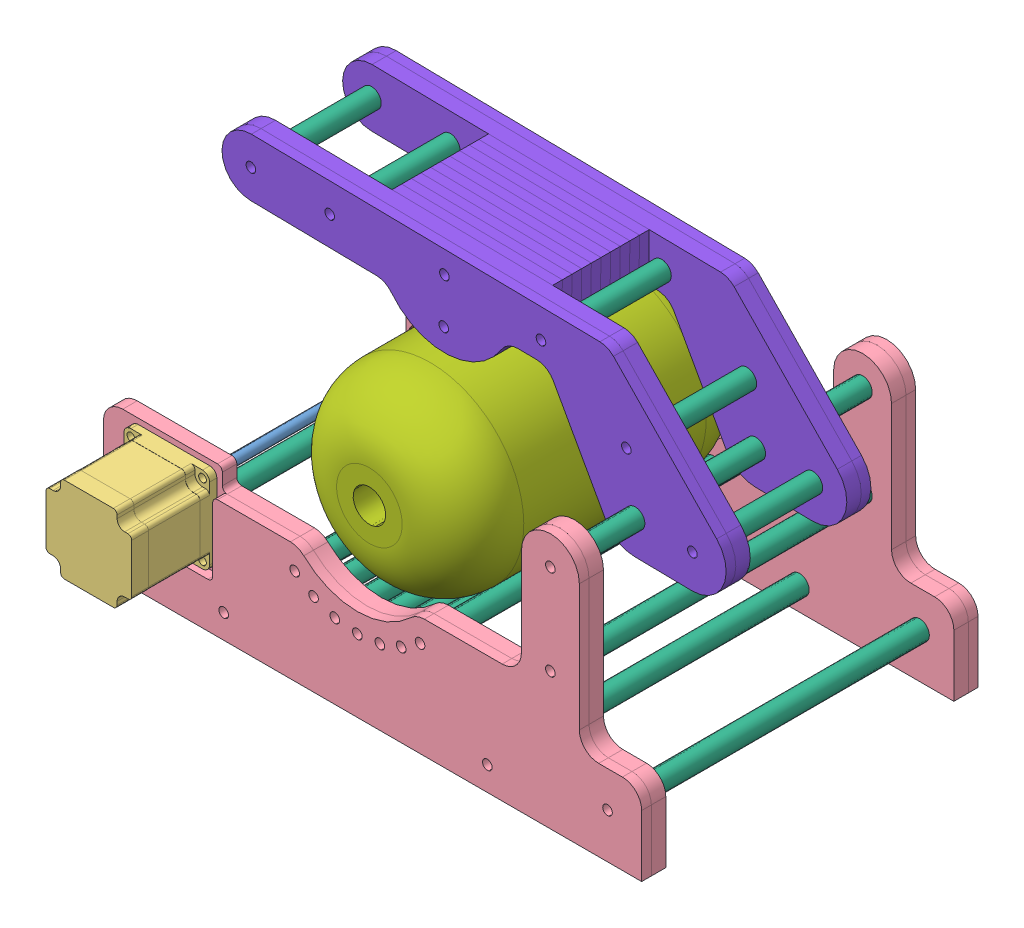
SolidWorks assembly ULTIMA_Respirator_main_assembly, configuration Défaut. Lengths in mm.
Overall size (361.61 241.93 320.57).
31 component instances, 8 part files, 27 mates.
Components (placement in the parent):
- McMaster-1257K65-1: McMaster-1257K65 [1257K114] at origin size (6.35 6.35 152.4)
- McMaster-6208K524-1: McMaster-6208K524 [6208K524] at (0 0 -87.63) x (0.967765 0.251857 0) z (0 0 1) size (25.41 25.4 38.1)
- Nema 23 Stepper Motor-1: Nema 23 Stepper Motor [Défaut] at (0 0 -111.455) size (56.4 56.4 76.6)
- ULTIMA_Respirator-01-1: ULTIMA_Respirator-01 [cote_droit] at (0 0 -111.455) size (360.46 168.25 15.88)
- McMaster-61005K311-1: McMaster-61005K311 [61005K311] at (0 0 76.3588) x (0 0 -1) z (0.997278 0.073738 0) size (25.4 15.88 15.87)
- Nema 23 Stepper Motor-2: Nema 23 Stepper Motor [Défaut] at (0 0 97.1175) x (-1 0 0) z (0 0 -1) size (56.4 56.4 76.6)
- ULTIMA_Respirator-01-2: ULTIMA_Respirator-01 [cote_gauche] at (0 0 87.5925) size (360.46 168.25 15.88)
- McMaster-89965K492-1: McMaster-89965K492 [8in] at (-31.6257 -46.1559 97.1175) x (0 0 -1) z (0.005772 0.999983 0) size (208.57 12.7 12.7)
- McMaster-89965K492-3: McMaster-89965K492 [8in] at (85.76 2.5142 97.1175) x (0 0 -1) z (0.005772 0.999983 0) size (208.57 12.7 12.7)
- McMaster-89965K492-4: McMaster-89965K492 [8in] at (98.1716 -5.7789 97.1175) x (0 0 -1) z (0.005772 0.999983 0) size (208.57 12.7 12.7)
- McMaster-89965K492-5: McMaster-89965K492 [8in] at (127 -12.7 97.1175) x (0 0 -1) z (0.005772 0.999983 0) size (208.57 12.7 12.7)
- McMaster-89965K492-6: McMaster-89965K492 [8in] at (141.8238 -10.9455 97.1175) x (0 0 -1) z (0.005772 0.999983 0) size (208.57 12.7 12.7)
- McMaster-89965K492-7: McMaster-89965K492 [8in] at (112.1762 -10.9455 97.1175) x (0 0 -1) z (0.005772 0.999983 0) size (208.57 12.7 12.7)
- McMaster-89965K492-8: McMaster-89965K492 [8in] at (155.8284 -5.7789 97.1175) x (0 0 -1) z (0.005772 0.999983 0) size (208.57 12.7 12.7)
- McMaster-89965K492-9: McMaster-89965K492 [8in] at (168.24 2.5142 97.1175) x (0 0 -1) z (0.005772 0.999983 0) size (208.57 12.7 12.7)
- McMaster-89965K492-10: McMaster-89965K492 [8in] at (39.0404 -44.4791 97.1175) x (0 0 -1) z (0.005772 0.999983 0) size (208.57 12.7 12.7)
- McMaster-89965K492-11: McMaster-89965K492 [8in] at (212.5171 -44.4791 97.1175) x (0 0 -1) z (0.005772 0.999983 0) size (208.57 12.7 12.7)
- McMaster-89965K492-12: McMaster-89965K492 [8in] at (291.5916 -30.7687 97.1175) x (0 0 -1) z (0.005772 0.999983 0) size (208.57 12.7 12.7)
- McMaster-89965K492-13: McMaster-89965K492 [8in] at (254 29.6105 97.1175) x (0 0 -1) z (0.005772 0.999983 0) size (208.57 12.7 12.7)
- McMaster-89965K492-14: McMaster-89965K492 [8in] at (254 88.9 97.1175) x (0 0 -1) z (0.005772 0.999983 0) size (208.57 12.7 12.7)
- approximative_ambubag_pump_volume-1: approximative_ambubag_pump_volume [Défaut] at (127.2504 56.684 -4.1981) x (0 0 1) z (-0.993068 -0.117537 0) size (200 123.16 123.16)
- ULTIMA_Respirator-02-1: ULTIMA_Respirator-02 [cote_gauche] at (-1.3727 4.0237 31.75) x (0.999875 -0.015798 0) z (0 0 1) size (332.87 211.28 47.62)
- McMaster-89965K492-16: McMaster-89965K492 [3.25] at (1.1278 162.2879 41.275) x (0 0 -1) z (0.005772 0.999983 0) size (82.55 12.7 12.7)
- McMaster-89965K492-17: McMaster-89965K492 [3.25] at (52.9818 161.4687 41.275) x (0 0 -1) z (0.005772 0.999983 0) size (82.55 12.7 12.7)
- McMaster-89965K492-18: McMaster-89965K492 [3.25] at (128.4323 164.7062 41.275) x (0 0 -1) z (0.005772 0.999983 0) size (82.55 12.7 12.7)
- McMaster-89965K492-19: McMaster-89965K492 [3.25] at (127.961 134.8809 41.275) x (0 0 -1) z (0.005772 0.999983 0) size (82.55 12.7 12.7)
- McMaster-89965K492-20: McMaster-89965K492 [3.25] at (191.9677 159.2727 41.275) x (0 0 -1) z (0.005772 0.999983 0) size (82.55 12.7 12.7)
- McMaster-89965K492-21: McMaster-89965K492 [3.25] at (248.1556 125.8527 41.275) x (0 0 -1) z (0.005772 0.999983 0) size (82.55 12.7 12.7)
- McMaster-89965K492-22: McMaster-89965K492 [3.25] at (291.587 88.3061 41.275) x (0 0 -1) z (0.005772 0.999983 0) size (82.55 12.7 12.7)
- McMaster-89965K492-23: McMaster-89965K492 [3.25] at (1.1278 162.2879 41.275) x (0 0 -1) z (0.005772 0.999983 0) size (82.55 12.7 12.7)
- ULTIMA_Respirator-02-3: ULTIMA_Respirator-02 [cote_droite] at (-1.3727 4.0237 -41.275) x (0.999875 -0.015798 0) z (0 0 1) size (332.87 211.28 47.62)
Mates (geometry in assembly coordinates):
- Concentric1: concentric: cylinder of Nema 23 Stepper Motor-1 through (-0.1601 -1.1209 114.9) axis (0 0 -1) radius 3.175; cylinder of ? through (-0.1601 -1.1209 111.4419) axis (0 0 1) radius 3.175
- Concentric2: concentric: cylinder of Nema 23 Stepper Motor-1 through (0 0 -90.855) axis (0 0 -1) radius 3.175; cylinder of McMaster-6208K524-1 through (0 0 -106.68) axis (0 0 1) radius 3.175
- Concentric3: concentric: cylinder of McMaster-6208K524-1 through (0 0 -68.58) axis (0 0 -1) radius 3.175; cylinder of McMaster-1257K65-1 through (0 0 76.2) axis (0 0 -1) radius 3.175
- Coincident1: coincident: plane of McMaster-6208K524-1 through (0 0 -76.2) normal (0 0 -1); plane of McMaster-1257K65-1 through (0 0 -76.2) normal (0 0 -1)
- Concentric4: concentric: cylinder of McMaster-1257K65-1 through (0 0 76.2) axis (0 0 -1) radius 3.175; cylinder of McMaster-61005K311-1 through (0 0 89.0588) axis (0 0 1) radius 3.175
- Coincident2: coincident: plane of McMaster-1257K65-1 through (0 0 76.2) normal (0 0 1); plane of McMaster-61005K311-1 through (8.5012 -7.3306 76.2) normal (0 0 1)
- Distance1: distance = 3.175 mm: plane of Nema 23 Stepper Motor-1 through (0 0 -109.855) normal (0 0 1); plane of McMaster-6208K524-1 through (0 0 -106.68) normal (0 0 -1)
- Coincident3: coordinate: point of McMaster-1257K65-1; point of assembly
- Parallel1: parallel: plane of McMaster-1257K65-1 through (0 0 0) normal (0 1 0); plane of Nema 23 Stepper Motor-1 through (0 0 -111.455) normal (0 1 0)
- Concentric5: concentric: cylinder of McMaster-61005K311-1 through (0 0 89.0588) axis (0 0 1) radius 3.175; cylinder of Nema 23 Stepper Motor-2 through (0 0 76.5175) axis (0 0 1) radius 3.175
- Coincident4: coincident: plane of McMaster-61005K311-1 through (8.5012 -7.3306 76.5175) normal (0 0 -1); plane of Nema 23 Stepper Motor-2 through (0 0 76.5175) normal (0 0 -1)
- Parallel2: parallel: plane of McMaster-1257K65-1 through (0 0 0) normal (0 1 0); plane of Nema 23 Stepper Motor-2 through (0 0 97.1175) normal (0 1 0)
- Concentric6: concentric: cylinder of Nema 23 Stepper Motor-1 through (0 0 -109.855) axis (0 0 -1) radius 19.05; cylinder of ULTIMA_Respirator-01-1 through (0 0 -101.93) axis (0 0 -1) radius 19.05
- Coincident5: coincident: plane of Nema 23 Stepper Motor-1 through (-23.6 23.6 -111.455) normal (0 0 1); plane of ULTIMA_Respirator-01-1 through (301.356 -19.7831 -111.455) normal (0 0 -1)
- Parallel3: parallel: plane of Nema 23 Stepper Motor-1 through (16.07 28.1 -156.455) normal (0 1 0); plane of ULTIMA_Respirator-01-1 through (-33.7088 31.8249 -101.93) normal (0 1 0)
- Concentric7: concentric: cylinder of Nema 23 Stepper Motor-2 through (0 0 95.5175) axis (0 0 1) radius 19.05; cylinder of ULTIMA_Respirator-01-2 through (0 0 97.1175) axis (0 0 -1) radius 19.05
- Coincident6: coincident: plane of Nema 23 Stepper Motor-2 through (23.6 23.6 97.1175) normal (0 0 -1); plane of ULTIMA_Respirator-01-2 through (301.356 -19.7831 97.1175) normal (0 0 1)
- Parallel4: parallel: plane of Nema 23 Stepper Motor-2 through (-16.07 28.1 142.1175) normal (0 1 0); plane of ULTIMA_Respirator-01-2 through (-33.7088 31.8249 97.1175) normal (0 1 0)
- Concentric9: concentric: cylinder of ULTIMA_Respirator-01-1 through (-31.6257 -46.1559 -101.93) axis (0 0 -1) radius 6.35; cylinder of McMaster-89965K492-1 through (-31.6257 -46.1559 -111.4546) axis (0 0 1) radius 6.35
- Coincident10: coincident: plane of ULTIMA_Respirator-01-2 through (301.356 -19.7831 97.1175) normal (0 0 1); plane of McMaster-89965K492-1 through (-31.6257 -46.1559 97.1175) normal (0 0 1)
- Concentric10: concentric: cylinder of McMaster-89965K492-14 through (254 88.9 -111.4546) axis (0 0 1) radius 6.35; cylinder of ULTIMA_Respirator-02-1 through (254 88.9 41.275) axis (0 0 -1) radius 6.35
- Distance2: distance = 31.75 mm: point of McMaster-1257K65-1; plane of ULTIMA_Respirator-02-1 through (254 88.9 31.75) normal (0 0 -1)
- Concentric11: concentric: cylinder of ULTIMA_Respirator-02-1 through (1.1278 162.2879 41.275) axis (0 0 -1) radius 6.35; cylinder of McMaster-89965K492-16 through (1.1278 162.2879 -41.275) axis (0 0 1) radius 6.35
- Coincident12: coincident: plane of ULTIMA_Respirator-02-1 through (254 88.9 41.275) normal (0 0 1); plane of McMaster-89965K492-16 through (1.1278 162.2879 41.275) normal (0 0 1)
- Concentric12: concentric: cylinder of McMaster-89965K492-14 through (254 88.9 -111.4546) axis (0 0 1) radius 6.35; cylinder of ULTIMA_Respirator-02-3 through (254 88.9 -31.75) axis (0 0 -1) radius 6.35
- Parallel5: parallel: plane of ULTIMA_Respirator-02-1 through (1.4287 181.3356 41.275) normal (0.015798 0.999875 0); plane of ULTIMA_Respirator-02-3 through (1.4287 181.3356 -31.75) normal (0.015798 0.999875 0)
- Distance3: distance = 31.75 mm: point of McMaster-1257K65-1; plane of ULTIMA_Respirator-02-3 through (254 88.9 -31.75) normal (0 0 1)
